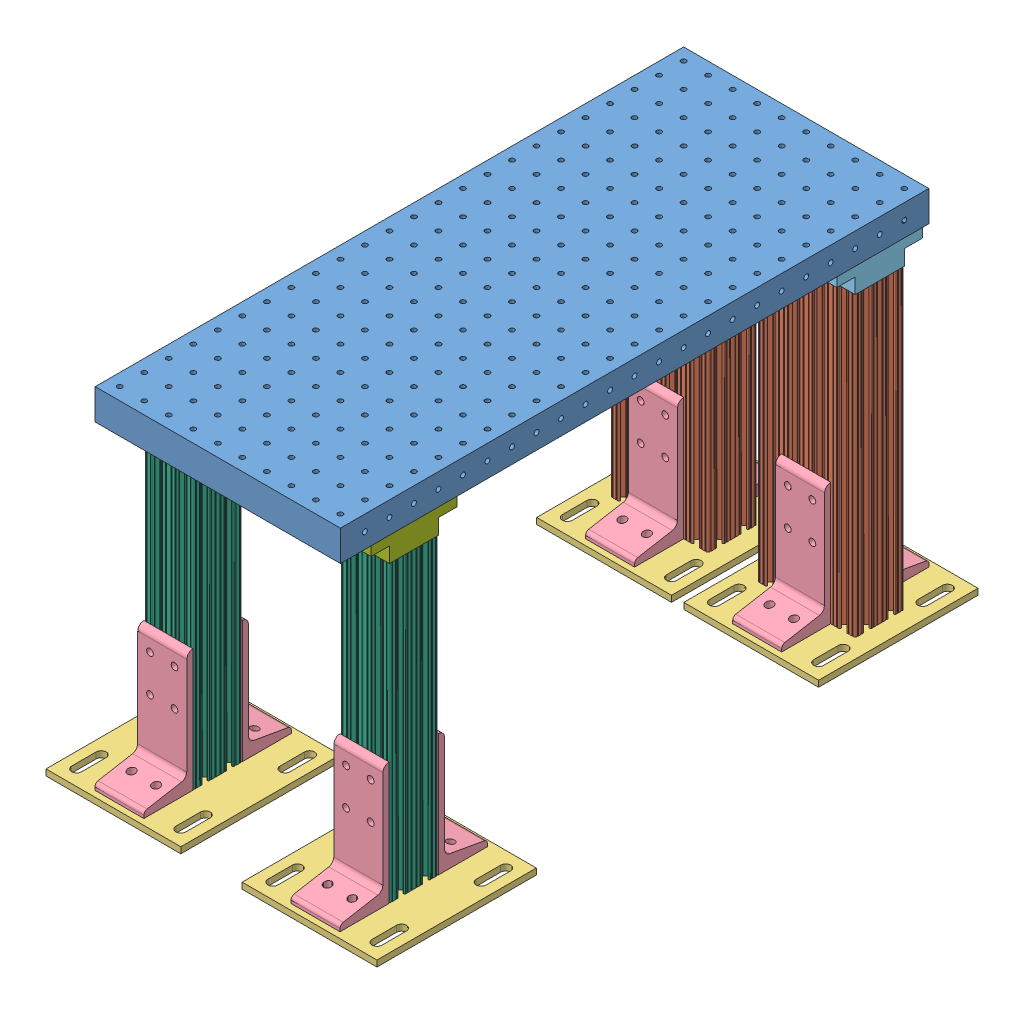
SolidWorks assembly slower breadboard assembly, configuration Default. Lengths in mm.
Overall size (342.9 371.48 648.11).
29 component instances, 7 part files, 12 mates.
Components (placement in the parent):
- slower breadboard-1: slower breadboard [Default] at (-355.032 28.4648 168.007) size (254 31.75 609.6)
- breadboard support leg assembly-2: breadboard support leg assembly [Default] at (-190.7934 -226.7491 -354.5875) x (0 0 1) z (0 -1 0) size (165.1 139.7 339.72)
  - 8020-2040 leg for breadboard support-1: 8020-2040 leg for breadboard support [Default] at (-48.9055 -77.0614 78.1612) size (50.8 101.6 307.98)
  - 8020-2387-DEFAULT-1: 8020-2387-DEFAULT [Default] at (-34.9863 -22.6888 91.8816) x (0 1 0) z (-1 0 0) size (139.7 133.35 165.1)
    - 8020-2387-DEFAULT_238708-1: 8020-2387-DEFAULT_238708 [Default] at (-67.1549 7.3704 27.8119) size (139.7 6.35 165.1)
    - 8020-2387-DEFAULT_238509-1: 8020-2387-DEFAULT_238509 [Default] at (9.1264 0.0214 49.7635) x (0 0 1) z (-1 0 0) size (50.8 127 50.8)
    - 8020-2387-DEFAULT_238509-2: 8020-2387-DEFAULT_238509 [Default] at (-41.6736 0.0214 -46.9187) x (0 0 -1) z (1 0 0) size (50.8 127 50.8)
  - breadboard support leg top bracket-1: breadboard support leg top bracket [Default] at (-61.6055 -89.7614 -229.8138) x (0 1 0) z (-1 0 0) size (101.6 25.4 88.9)
- breadboard support leg assembly-4: breadboard support leg assembly [Default] at (-343.1934 -226.7491 -354.5875) x (0 0 1) z (0 -1 0) size (165.1 139.7 339.72)
  - 8020-2040 leg for breadboard support-1: 8020-2040 leg for breadboard support [Default] at (-48.9055 -77.0614 78.1612) size (50.8 101.6 307.98)
  - 8020-2387-DEFAULT-1: 8020-2387-DEFAULT [Default] at (-34.9863 -22.6888 91.8816) x (0 1 0) z (-1 0 0) size (139.7 133.35 165.1)
    - 8020-2387-DEFAULT_238708-1: 8020-2387-DEFAULT_238708 [Default] at (-67.1549 7.3704 27.8119) size (139.7 6.35 165.1)
    - 8020-2387-DEFAULT_238509-1: 8020-2387-DEFAULT_238509 [Default] at (9.1264 0.0214 49.7635) x (0 0 1) z (-1 0 0) size (50.8 127 50.8)
    - 8020-2387-DEFAULT_238509-2: 8020-2387-DEFAULT_238509 [Default] at (-41.6736 0.0214 -46.9187) x (0 0 -1) z (1 0 0) size (50.8 127 50.8)
  - breadboard support leg top bracket-1: breadboard support leg top bracket [Default] at (-61.6055 -89.7614 -229.8138) x (0 1 0) z (-1 0 0) size (101.6 25.4 88.9)
- breadboard support leg assembly 2020-1: breadboard support leg assembly 2020 [Default] at (-308.7033 -135.8388 95.4171) x (1 0 0) z (0 -1 0) size (139.7 165.1 336.55)
  - 8020-2020-1: 8020-2020 [Default] at (-20.9287 -3.61 165.8964) size (50.8 50.8 304.8)
  - breadboard support leg top bracket 2020-1: breadboard support leg top bracket 2020 [Default] at (-46.3287 21.79 -138.9036) x (1 0 0) z (0 1 0) size (50.8 25.4 88.9)
  - 8020-2387-DEFAULT-1: 8020-2387-DEFAULT [Default] at (-4.6551 -4.8293 179.6168) x (1 0 0) z (0 1 0) size (139.7 133.35 165.1)
    - 8020-2387-DEFAULT_238708-1: 8020-2387-DEFAULT_238708 [Default] at (-67.1549 7.3704 27.8119) size (139.7 6.35 165.1)
    - 8020-2387-DEFAULT_238509-1: 8020-2387-DEFAULT_238509 [Default] at (9.1264 0.0214 49.7635) x (0 0 1) z (-1 0 0) size (50.8 127 50.8)
    - 8020-2387-DEFAULT_238509-2: 8020-2387-DEFAULT_238509 [Default] at (-41.6736 0.0214 -46.9187) x (0 0 -1) z (1 0 0) size (50.8 127 50.8)
- breadboard support leg assembly 2020-2: breadboard support leg assembly 2020 [Default] at (-105.5033 -135.8388 95.4171) x (1 0 0) z (0 -1 0) size (139.7 165.1 336.55)
  - 8020-2020-1: 8020-2020 [Default] at (-20.9287 -3.61 165.8964) size (50.8 50.8 304.8)
  - breadboard support leg top bracket 2020-1: breadboard support leg top bracket 2020 [Default] at (-46.3287 21.79 -138.9036) x (1 0 0) z (0 1 0) size (50.8 25.4 88.9)
  - 8020-2387-DEFAULT-1: 8020-2387-DEFAULT [Default] at (-4.6551 -4.8293 179.6168) x (1 0 0) z (0 1 0) size (139.7 133.35 165.1)
    - 8020-2387-DEFAULT_238708-1: 8020-2387-DEFAULT_238708 [Default] at (-67.1549 7.3704 27.8119) size (139.7 6.35 165.1)
    - 8020-2387-DEFAULT_238509-1: 8020-2387-DEFAULT_238509 [Default] at (9.1264 0.0214 49.7635) x (0 0 1) z (-1 0 0) size (50.8 127 50.8)
    - 8020-2387-DEFAULT_238509-2: 8020-2387-DEFAULT_238509 [Default] at (-41.6736 0.0214 -46.9187) x (0 0 -1) z (1 0 0) size (50.8 127 50.8)
Mates (geometry in assembly coordinates):
- Parallel2: parallel anti-aligned: line of slower breadboard-1 through (-101.032 28.4648 -441.593) axis (-1 0 0); line of breadboard support leg assembly-4/breadboard support leg top bracket-1 through (-278.832 28.4648 -282.843) axis (1 0 0)
- Concentric2: concentric aligned: circle of breadboard support leg assembly-4/breadboard support leg top bracket-1; circle of slower breadboard-1
- Coincident4: coincident anti-aligned: plane of slower breadboard-1 through (-355.032 28.4648 -441.593) normal (0 -1 0); plane of breadboard support leg assembly-4/breadboard support leg top bracket-1 through (-253.432 28.4648 -212.993) normal (0 1 0)
- Parallel3: parallel anti-aligned: line of slower breadboard-1 through (-101.032 28.4648 -441.593) axis (-1 0 0); line of breadboard support leg assembly-2/breadboard support leg top bracket-1 through (-126.432 28.4648 -282.843) axis (1 0 0)
- Coincident6: coincident anti-aligned: plane of slower breadboard-1 through (-355.032 28.4648 -441.593) normal (0 -1 0); plane of breadboard support leg assembly-2/breadboard support leg top bracket-1 through (-101.032 28.4648 -212.993) normal (0 1 0)
- Concentric9: concentric aligned: circle of breadboard support leg assembly-2/breadboard support leg top bracket-1; circle of slower breadboard-1
- Concentric10: concentric aligned: circle of breadboard support leg assembly 2020-1/breadboard support leg top bracket 2020-1; circle of slower breadboard-1
- Parallel4: parallel aligned: plane of slower breadboard-1 through (-355.032 60.2148 168.007) normal (-1 0 0); plane of breadboard support leg assembly 2020-1/breadboard support leg top bracket 2020-1 through (-355.032 28.4648 117.207) normal (-1 0 0)
- Coincident8: coincident anti-aligned: plane of slower breadboard-1 through (-355.032 28.4648 -441.593) normal (0 -1 0); plane of breadboard support leg assembly 2020-1/breadboard support leg top bracket 2020-1 through (-355.032 28.4648 66.407) normal (0 1 0)
- Concentric11: concentric aligned: circle of breadboard support leg assembly 2020-2/breadboard support leg top bracket 2020-1; circle of slower breadboard-1
- Parallel5: parallel: plane of slower breadboard-1 through (-101.032 60.2148 168.007) normal (1 0 0); plane of breadboard support leg assembly 2020-2/breadboard support leg top bracket 2020-1 through (-75.632 28.4648 117.207) normal (1 0 0)
- Coincident10: coincident: plane of slower breadboard-1 through (-355.032 28.4648 -441.593) normal (0 -1 0); plane of breadboard support leg assembly 2020-2/breadboard support leg top bracket 2020-1 through (-126.432 28.4648 66.407) normal (0 1 0)
